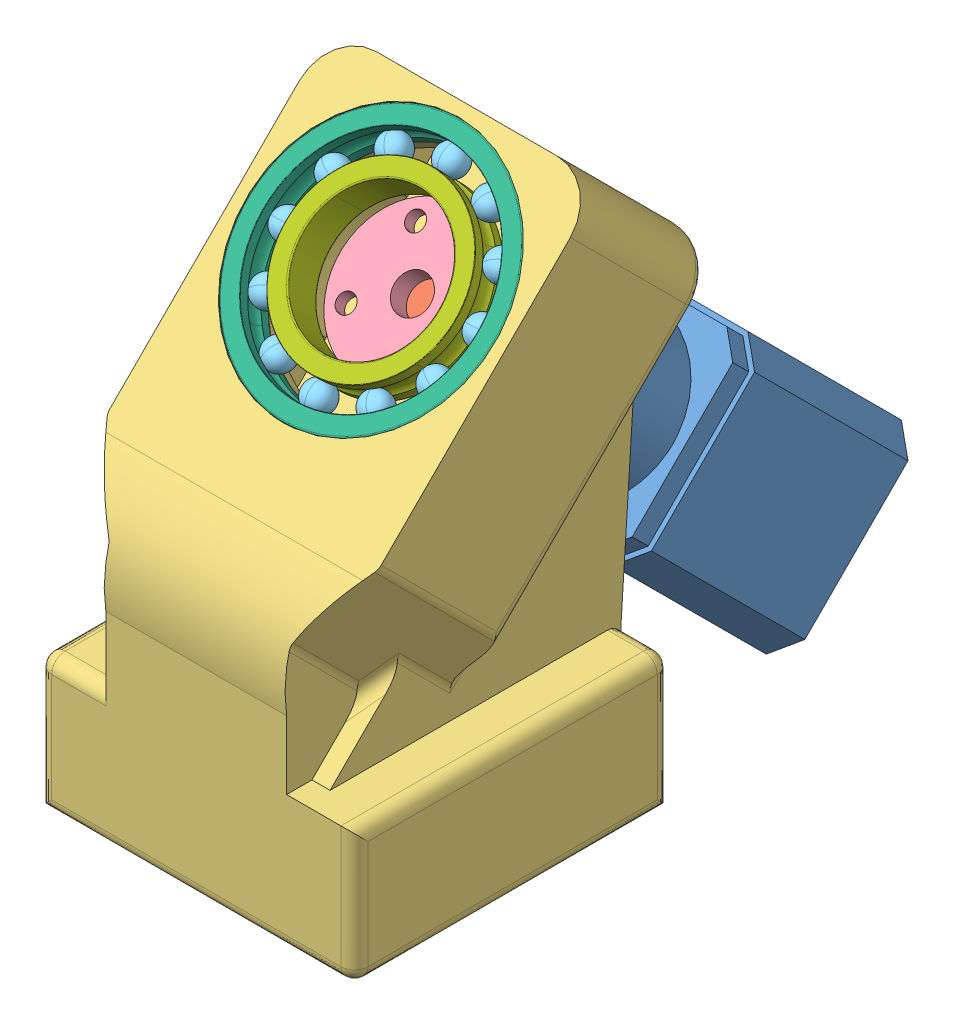
SolidWorks assembly assieme_Spalla_new, configuration Default. Lengths in mm.
Overall size (74.81 127.68 140.24).
20 component instances, 7 part files, 14 mates.
Components (placement in the parent):
- motore_spalla-1: motore_spalla [Default] at (7.2961 -48.9495 -116.1114) x (1 0.000382 -0.000382) z (0 0.707107 0.707107) size (42.3 42.3 104) (flexible)
  - 17HS19-1684S-PG14-1: 17HS19-1684S-PG14 [Default] at (-7.2931 5.4422 42.5) size (42.3 42.3 85)
  - albero_motore-1: albero_motore [Default] at (-7.2931 5.4422 127.5) x (0 0 1) z (-0.943838 0.330409 0) size (19 8 8)
- supporto_spalla_NUOVO-1: supporto_spalla_NUOVO [Default] x (1 0 0) z (0 -1 0) size (70 86.55 122.43)
- flangia_spalla-1: flangia_spalla [Default] at (0 62.0226 -12.8302) x (0.537947 -0.596076 0.596076) z (0 -0.707107 -0.707107) size (32 32 13)
- SKF_16006-1: SKF_16006 [Default] at (0 71.215 -3.6378) x (0 -0.707107 -0.707107) z (0.873766 -0.343899 0.343899) size (9 55 55)
  - SKF_16006_16-1: SKF_16006_16 [Default] x (1 0 0) z (0 -0.5 0.866025) size (6.35 6.35 6.35)
  - SKF_16006_16-2: SKF_16006_16 [Default] x (1 0 0) z (0 -0.866025 0.5) size (6.35 6.35 6.35)
  - SKF_16006_16-3: SKF_16006_16 [Default] x (1 0 0) z (0 -1 0) size (6.35 6.35 6.35)
  - SKF_16006_16-4: SKF_16006_16 [Default] x (1 0 0) z (0 -0.866025 -0.5) size (6.35 6.35 6.35)
  - SKF_16006_16-5: SKF_16006_16 [Default] x (1 0 0) z (0 -0.5 -0.866025) size (6.35 6.35 6.35)
  - SKF_16006_16-6: SKF_16006_16 [Default] x (1 0 0) z (0 0 -1) size (6.35 6.35 6.35)
  - SKF_16006_16-7: SKF_16006_16 [Default] x (1 0 0) z (0 0.5 -0.866025) size (6.35 6.35 6.35)
  - SKF_16006_16-8: SKF_16006_16 [Default] x (1 0 0) z (0 0.866025 -0.5) size (6.35 6.35 6.35)
  - SKF_16006_16-9: SKF_16006_16 [Default] x (1 0 0) z (0 1 0) size (6.35 6.35 6.35)
  - SKF_16006_16-10: SKF_16006_16 [Default] x (1 0 0) z (0 0.866025 0.5) size (6.35 6.35 6.35)
  - SKF_16006_16-11: SKF_16006_16 [Default] x (1 0 0) z (0 0.5 0.866025) size (6.35 6.35 6.35)
  - SKF_16006_16-12: SKF_16006_16 [Default] at origin size (6.35 6.35 6.35)
  - SKF_16006_29-1: SKF_16006_29 [Default] at origin size (9 55 55)
  - SKF_16006_31-1: SKF_16006_31 [Default] at origin size (9 37.7 37.7)
Mates (geometry in assembly coordinates):
- Coincidente1: coincident aligned: plane of supporto_spalla_NUOVO-1 through (0 0 0) normal (0 0 1)
- Coincidente2: coincident anti-aligned: plane of supporto_spalla_NUOVO-1 through (0 0 0) normal (0 -1 0)
- Coincidente3: coincident aligned: plane of supporto_spalla_NUOVO-1 through (0 0 0) normal (1 0 0)
- Concentrico1: concentric aligned: cylinder of motore_spalla-1/17HS19-1684S-PG14-1 through (0 43.6378 -31.215) axis (0 -0.707107 -0.707107) radius 18; cylinder of supporto_spalla_NUOVO-1 through (0 45.4056 -29.4472) axis (0 -0.707107 -0.707107) radius 11.1
- Concentrico2: concentric anti-aligned: circle of motore_spalla-1/17HS19-1684S-PG14-1; circle of supporto_spalla_NUOVO-1
- Coincidente4: coincident anti-aligned: plane of motore_spalla-1/17HS19-1684S-PG14-1 through (0 43.6378 -31.215) normal (0 0.707107 0.707107); plane of supporto_spalla_NUOVO-1 through (20 57.78 -45.3571) normal (0 -0.707107 -0.707107)
- Concentrico4: concentric aligned: cylinder of motore_spalla-1/albero_motore-1 through (0 58.4871 -16.3657) axis (0 -0.707107 -0.707107) radius 4; cylinder of flangia_spalla-1 through (0 62.0226 -12.8302) axis (0 -0.707107 -0.707107) radius 4
- Concentrico5: concentric aligned: cylinder of supporto_spalla_NUOVO-1 through (0 71.215 -3.6378) axis (0 -0.707107 -0.707107) radius 27.575; cylinder of Bearig 8x22x7-1 through (0 72.9828 -1.8701) axis (0 -0.707107 -0.707107) radius 11
- Concentrico7: concentric aligned: cylinder of motore_spalla-1/albero_motore-1 through (0 58.4871 -16.3657) axis (0 -0.707107 -0.707107) radius 4; cylinder of Bearig 8x22x7-2 through (0 46.8198 -28.033) axis (0 -0.707107 -0.707107) radius 4
- Coincidente10: coincident anti-aligned: plane of supporto_spalla_NUOVO-1 through (0 41.8701 -32.9828) normal (0 0.707107 0.707107); plane of Bearig 8x22x7-2 through (0 41.8701 -32.9828) normal (0 -0.707107 -0.707107)
- Coincidente11: coincident anti-aligned: plane of supporto_spalla_NUOVO-1 through (0 69.0937 -5.7591) normal (0 -0.707107 -0.707107); plane of Bearig 8x22x7-1 through (0 72.9828 -1.8701) normal (0 0.707107 0.707107)
- Concentrico8: concentric anti-aligned: cylinder of motore_spalla-1/albero_motore-1 through (0 58.4871 -16.3657) axis (0 -0.707107 -0.707107) radius 4; cylinder of flangia_spalla-1 through (0 52.8302 -22.0226) axis (0 0.707107 0.707107) radius 8
- Concentrico9: concentric aligned: cylinder of supporto_spalla_NUOVO-1 through (0 71.215 -3.6378) axis (0 -0.707107 -0.707107) radius 27.575; cylinder of SKF_16006-1/SKF_16006_29-1 through (0 35.8597 -38.9932) axis (0 -0.707107 -0.707107) radius 27.5
- Larghezza1: width anti-aligned: plane of supporto_spalla_NUOVO-1 through (30 76.8718 -26.2652) normal (0 -0.707107 -0.707107); plane of flangia_spalla-1 through (20 66.2652 -36.8718) normal (0 0.707107 0.707107); plane of supporto_spalla_NUOVO-1 through (0 62.0226 -12.8302) normal (0 0.707107 0.707107); plane of flangia_spalla-1 through (0 52.8302 -22.0226) normal (0 -0.707107 -0.707107)
